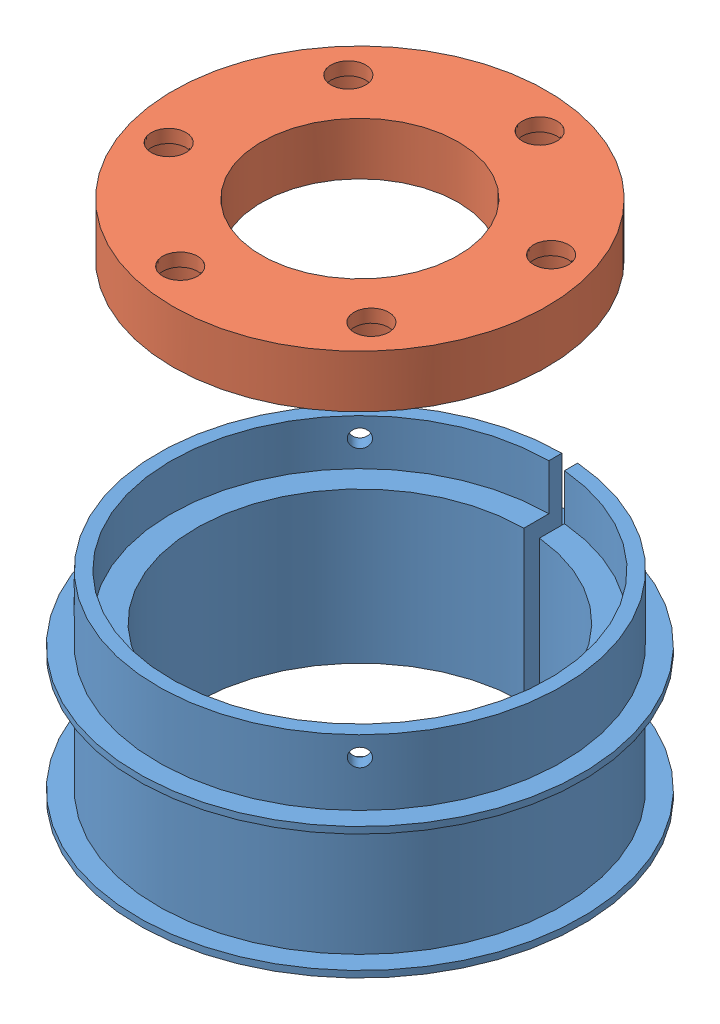
SolidWorks assembly Assembly, configuration Default. Lengths in mm.
Overall size (85.85 100.34 85.85).
2 component instances, 2 part files, 1 mates.
Components (placement in the parent):
- Coil mount-1: Coil mount [Default] at origin size (85.85 38.1 85.85)
- Viewport Washer 2.75-1: Viewport Washer 2.75 [Default] at (0 100.3395 0) x (0.978418 0 0.206633) z (0 -1 0) size (72.39 72.39 10.16)
Mates (geometry in assembly coordinates):
- Concentric1: concentric aligned: cylinder of Coil mount-1 through (0 29.21 0) axis (0 1 0) radius 36.576; cylinder of Viewport Washer 2.75-1 through (0 90.1795 0) axis (0 1 0) radius 36.195
